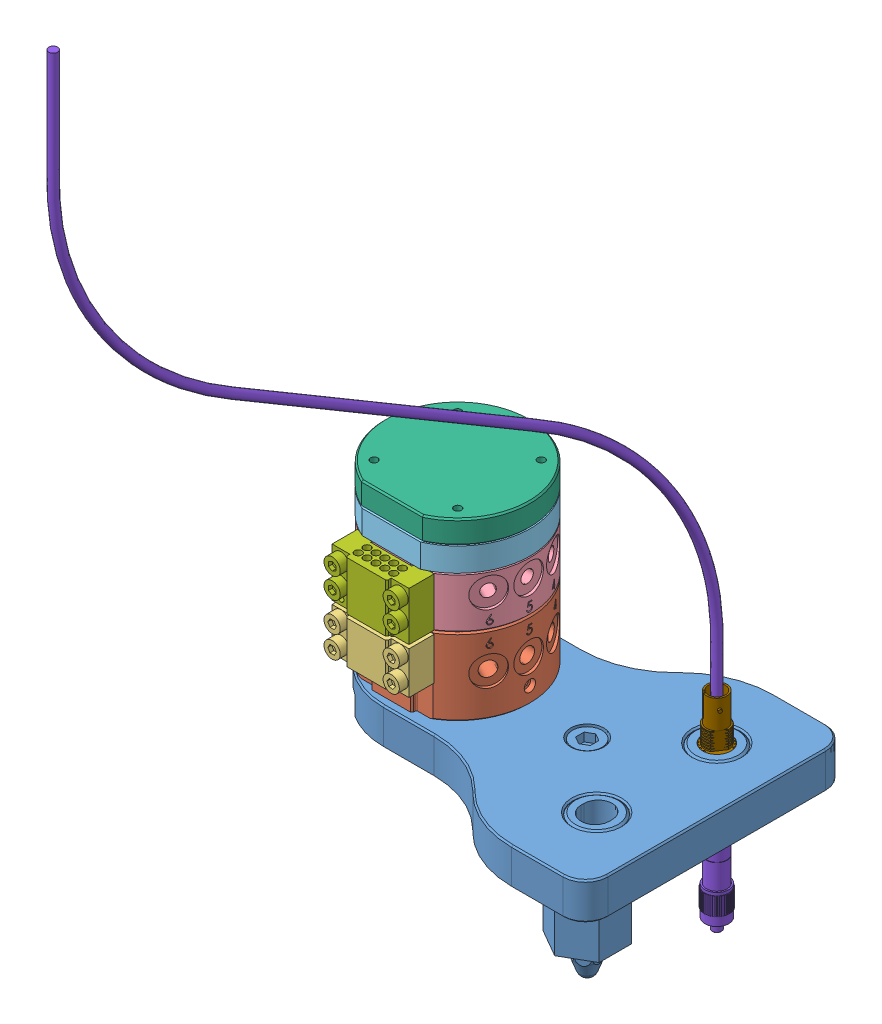
SolidWorks assembly Assem1, configuration Default. Lengths in mm.
Overall size (112.8 345.49 211.29).
11 component instances, 9 part files, 10 mates.
Components (placement in the parent):
- ATI-DEFAULT-1: ATI-DEFAULT [Default] at (14.0166 76.799 85.3041) x (0 0 -1) z (0 -1 0) size (88.9 112.8 77.77)
- ATI-9120-005T-E10-000-1: ATI-9120-005T-E10-000 [Flat A_E10_] at (14.0166 115.2546 85.3041) x (1 0 0) z (0 1 0) size (49 56.96 29.45)
  - ATI-9120-005T-E10-000_QC5-T-1: ATI-9120-005T-E10-000_QC5-T [Default] at origin size (49 46.95 29.45)
  - ATI-9120-005T-E10-000_E10T-005-1: ATI-9120-005T-E10-000_E10T-005 [Default] at (-13.0048 -25.9334 -0.7112) x (0 0 1) z (-1 0 0) size (14.76 17 26.01)
- ATI-9120-005M-E10-000-4259-1: ATI-9120-005M-E10-000-4259 [Flat A_E10_Interface Plate_Blank IP_] at (14.0172 137.7336 107.757) x (0 1 0) z (0.000017 0 1) size (52.37 49.02 56.97)
  - ATI-9120-005M-E10-000-4259_QC5-M-1: ATI-9120-005M-E10-000-4259_QC5-M [Default] at origin size (49.07 49 46.95)
  - ATI-9120-005M-E10-000-4259_1220-1: ATI-9120-005M-E10-000-4259_1220 [Default] at (3.0226 0 -22.4536) x (0 -1 0) z (-1 0 0) size (49.02 46.96 8)
  - ATI-9120-005M-E10-000-4259_4259-1: ATI-9120-005M-E10-000-4259_4259 [Default] at (10.8966 0 -22.4536) x (0 1 0) z (0 0 1) size (49 7.87 46.73)
  - ATI-9120-005M-E10-000-4259_E10M-005-1: ATI-9120-005M-E10-000-4259_E10M-005 [Default] at (-21.971 -13.0048 3.4798) x (-1 0 0) z (0 -1 0) size (18.26 17 26.01)
- FiberOpticConnector-1: FiberOpticConnector [Default] at (81.352 44.5605 64.9841) x (-0.209777 0 0.977749) z (0 -1 0) size (194.75 8.5 330.34)
- ST Bulkhead ConnectorSLDPRT-1: ST Bulkhead ConnectorSLDPRT [Default] at (81.352 89.245 64.9841) x (-0.833554 0 -0.552438) z (0 -1 0) size (9.53 9.48 29.21)
Mates (geometry in assembly coordinates):
- Concentric1: concentric aligned: cylinder of ATI-9120-005T-E10-000-1/ATI-9120-005T-E10-000_QC5-T-1 through (14.0166 115.2546 85.3041) axis (0 1 0) radius 12.446; cylinder of ATI-9120-005M-E10-000-4259-1/ATI-9120-005M-E10-000-4259_QC5-M-1 through (14.0168 142.0373 85.3034) axis (0 1 0) radius 9.3408
- Concentric2: concentric aligned: cylinder of ATI-9120-005T-E10-000-1/ATI-9120-005T-E10-000_QC5-T-1 through (18.2863 118.6938 69.3681) axis (0 -1 0) radius 2.4962; cylinder of ATI-9120-005M-E10-000-4259-1/ATI-9120-005M-E10-000-4259_QC5-M-1 through (18.2863 115.2546 69.3681) axis (0 -1 0) radius 2.5019
- Coincident3: coincident anti-aligned: plane of ATI-9120-005T-E10-000-1/ATI-9120-005T-E10-000_QC5-T-1 through (14.0166 115.2546 60.8058) normal (0 1 0); plane of ATI-9120-005M-E10-000-4259-1/ATI-9120-005M-E10-000-4259_QC5-M-1 through (31.0283 115.2546 90.5672) normal (0 -1 0)
- Concentric24: concentric aligned: cylinder of ATI-DEFAULT-1 through (14.0166 93.229 105.304) axis (0 -1 0) radius 1.5; cylinder of ATI-9120-005T-E10-000-1/ATI-9120-005T-E10-000_QC5-T-1 through (14.0166 89.245 105.304) axis (0 -1 0) radius 1.4986
- Parallel10: parallel aligned: plane of ATI-DEFAULT-1 through (44.268 89.245 110.4501) normal (0 0 1); plane of ATI-9120-005T-E10-000-1/ATI-9120-005T-E10-000_QC5-T-1 through (7.0443 89.245 107.7577) normal (0 0 1)
- Coincident5: coincident anti-aligned: plane of ATI-DEFAULT-1 through (14.0166 89.245 85.3041) normal (0 1 0); plane of ATI-9120-005T-E10-000-1/ATI-9120-005T-E10-000_QC5-T-1 through (14.0166 89.245 60.8058) normal (0 -1 0)
- Concentric25: concentric anti-aligned: cylinder of ATI-DEFAULT-1 through (81.352 76.799 64.9841) axis (0 1 0) radius 4.7625; cylinder of ST Bulkhead ConnectorSLDPRT-1 through (81.352 104.739 64.9841) axis (0 -1 0) radius 3.429
- Coincident6: coincident aligned: plane of ATI-DEFAULT-1 through (14.0166 89.245 85.3041) normal (0 1 0); plane of ST Bulkhead ConnectorSLDPRT-1 through (81.352 89.245 64.9841) normal (0 1 0)
- Concentric27: concentric anti-aligned: cylinder of FiberOpticConnector-1 through (81.352 34.5605 64.9841) axis (0 1 0) radius 1.575; cylinder of ST Bulkhead ConnectorSLDPRT-1 through (81.352 104.739 64.9841) axis (0 -1 0) radius 1.55
- Coincident7: coincident aligned: plane of FiberOpticConnector-1 through (75.1708 75.529 65.192) normal (0 -1 0); plane of ST Bulkhead ConnectorSLDPRT-1 through (81.352 75.529 64.9841) normal (0 -1 0)
